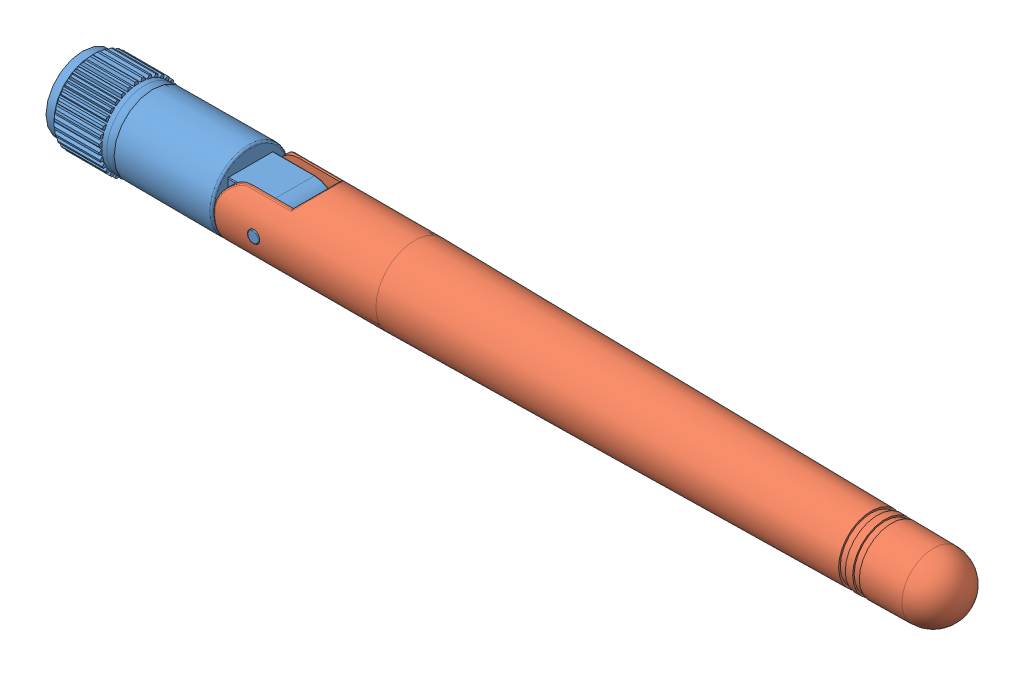
SolidWorks assembly Antenna assy, configuration 0. Lengths in mm.
Overall size (108.2 9.98 9.98).
2 component instances, 2 part files, 8 mates.
Components (placement in the parent):
- Antenna base-1: Antenna base [По умолчанию] at origin size (28.45 9.98 9.98)
- Antenna top-1: Antenna top [По умолчанию] at (20.7 0 0) size (87.5 9.5 9.5)
Mates (geometry in assembly coordinates):
- Совпадение1: coincident aligned: plane of Antenna base-1 through (0 0 0) normal (0 0 1); plane of assembly through (0 0 0) normal (0 0 1)
- Совпадение2: coincident aligned: plane of Antenna base-1 through (0 0 0) normal (0 1 0); plane of assembly through (0 0 0) normal (0 1 0)
- Совпадение3: coincident aligned: plane of Antenna base-1 through (0 0 0) normal (1 0 0); plane of assembly through (0 0 0) normal (1 0 0)
- Совпадение4: coincident aligned: plane of Antenna top-1 through (20.7 0 0) normal (0 0 1); plane of assembly through (0 0 0) normal (0 0 1)
- Концентричный1: concentric anti-aligned: cylinder of Antenna base-1 through (25.7 0 4.8) axis (0 0 -1) radius 0.75; cylinder of Antenna top-1 through (25.7 0 -4.75) axis (0 0 1) radius 0.75
- Параллельность1: parallel aligned: plane of Antenna top-1 through (20.7 0 0) normal (0 1 0); plane of assembly through (0 0 0) normal (0 1 0)
- Угол1: planar angle = 0.785398 rad: plane of Antenna top-1; plane of assembly through (0 0 0) normal (0 1 0)
- Угол2: planar angle = 1.570796 rad: plane of Antenna top-1; plane of assembly through (0 0 0) normal (0 1 0)
